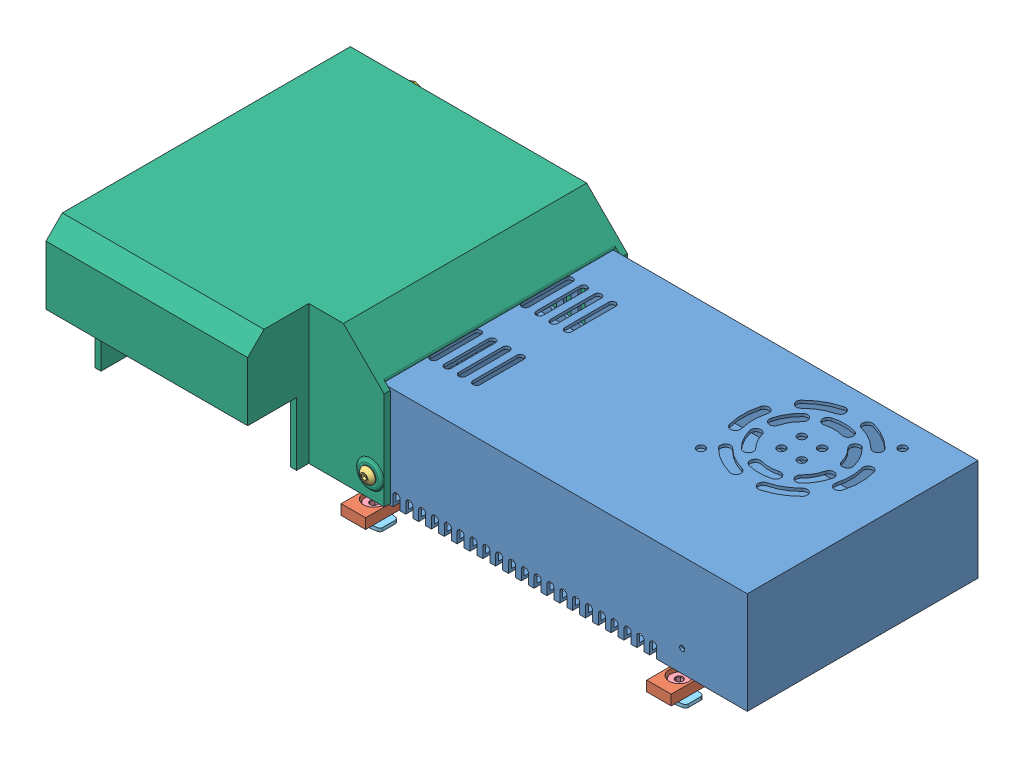
SolidWorks assembly Power_Supply ASMB, configuration Default. Lengths in mm.
21 component instances, 7 part files, 49 mates.
Components (placement in the parent):
- 360W_12V_Powersupply-1: 360W_12V_Powersupply [Default] at origin size (214 50 113.25)
- PSU Holder-1: PSU Holder [Default] at (75 0 0) x (0 0 1) z (0 -1 0) size (136 12 5)
- PSU Holder-2: PSU Holder [Default] at (-75 0 0) x (0 0 1) z (0 -1 0) size (136 12 5)
- M4 Buttonhead Bolt-1: M4 Buttonhead Bolt [M4 x 6mm] at (75 -4.2 25) x (1 0 0) z (0 -1 0) size (7.6 7.6 8.2)
- M4 Buttonhead Bolt-2: M4 Buttonhead Bolt [M4 x 6mm] at (75 -4.2 -25) x (1 0 0) z (0 -1 0) size (7.6 7.6 8.2)
- M4 Buttonhead Bolt-3: M4 Buttonhead Bolt [M4 x 6mm] at (-75 -4.2 -25) x (1 0 0) z (0 -1 0) size (7.6 7.6 8.2)
- M4 Buttonhead Bolt-4: M4 Buttonhead Bolt [M4 x 6mm] at (-75 -4.2 25) x (1 0 0) z (0 -1 0) size (7.6 7.6 8.2)
- Low Profile Screw M5-1: Low Profile Screw M5 [M5 x 8] at (75 -11 -58) x (0 -1 0) z (0 0 1) size (9.62 9 9)
- Low Profile Screw M5-2: Low Profile Screw M5 [M5 x 8] at (-75 -11 -58) x (0 -1 0) z (0 0 1) size (9.62 9 9)
- Low Profile Screw M5-3: Low Profile Screw M5 [M5 x 8] at (-75 -11 58) x (0 -1 0) z (0 0 1) size (9.62 9 9)
- Low Profile Screw M5-4: Low Profile Screw M5 [M5 x 8] at (75 -11 58) x (0 -1 0) z (0 0 1) size (9.62 9 9)
- Tee Nut-1: Tee Nut [Default] at (75 -6.8 -58) x (1 0 0) z (0 -1 0) size (15 10 3)
- Tee Nut-2: Tee Nut [Default] at (75 -6.8 58) x (1 0 0) z (0 -1 0) size (15 10 3)
- Tee Nut-3: Tee Nut [Default] at (-75 -6.8 58) x (1 0 0) z (0 -1 0) size (15 10 3)
- Tee Nut-4: Tee Nut [Default] at (-75 -6.8 -58) x (1 0 0) z (0 -1 0) size (15 10 3)
- Wiring Safety Cover-1: Wiring Safety Cover [Default] at (-144.75 65.8 -0.075) x (0 0 1) z (0 1 0) size (164.4 136 73.8)
- Amazon_Electrical_Fused_Plug-1: Amazon_Electrical_Fused_Plug [Default] at (-174.45 43.45 -59.775) x (0 1 0) z (0 0 -1) size (49 59 24.75)
- M4 Buttonhead Bolt-5: M4 Buttonhead Bolt [M4 x 8mm] at (-75 11.5 -62.975) x (-0.923728 -0.383049 0) z (0 0 -1) size (7.6 7.6 10.34)
- M4 Buttonhead Bolt-6: M4 Buttonhead Bolt [M4 x 8mm] at (-75 11.5 62.825) size (7.6 7.6 10.34)
- Low Profile Screw M5-5: Low Profile Screw M5 [M5 x 10] at (-176.25 -10 -65.775) x (0 -1 0) z (0 0 1) size (11.5 9 9)
- Tee Nut-5: Tee Nut [Default] at (-176.25 -6.8 -65.775) x (0 0 -1) z (0 -1 0) size (15 10 3)
Mates (geometry in assembly coordinates):
- Coincident1: coincident anti-aligned: plane of 360W_12V_Powersupply-1 through (0 0 0) normal (0 -1 0); plane of PSU Holder-1 through (75 0 0) normal (0 1 0)
- Coincident2: coincident anti-aligned: plane of 360W_12V_Powersupply-1 through (0 0 0) normal (0 -1 0); plane of PSU Holder-2 through (-75 0 0) normal (0 1 0)
- Concentric1: concentric anti-aligned: cylinder of 360W_12V_Powersupply-1 through (75 0 25) axis (0 -1 0) radius 1.65; cylinder of PSU Holder-1 through (75 -5 25) axis (0 1 0) radius 2.1
- Concentric2: concentric anti-aligned: cylinder of 360W_12V_Powersupply-1 through (75 0 -25) axis (0 -1 0) radius 1.65; cylinder of PSU Holder-1 through (75 -5 -25) axis (0 1 0) radius 2.1
- Concentric3: concentric anti-aligned: cylinder of 360W_12V_Powersupply-1 through (-75 0 25) axis (0 -1 0) radius 1.65; cylinder of PSU Holder-2 through (-75 -5 25) axis (0 1 0) radius 2.1
- Concentric4: concentric anti-aligned: cylinder of 360W_12V_Powersupply-1 through (-75 0 -25) axis (0 -1 0) radius 1.65; cylinder of PSU Holder-2 through (-75 -5 -25) axis (0 1 0) radius 2.1
- Concentric5: concentric anti-aligned: cylinder of 360W_12V_Powersupply-1 through (75 0 25) axis (0 -1 0) radius 1.65; cylinder of M4 Buttonhead Bolt-1 through (75 4 25) axis (0 1 0) radius 2
- Coincident3: coincident anti-aligned: plane of PSU Holder-1 through (-27.0469 -2 -48) normal (0 -1 0); plane of M4 Buttonhead Bolt-1 through (75 -2 21.2) normal (0 1 0)
- Concentric6: concentric anti-aligned: cylinder of 360W_12V_Powersupply-1 through (75 0 -25) axis (0 -1 0) radius 1.65; cylinder of M4 Buttonhead Bolt-2 through (75 4 -25) axis (0 1 0) radius 2
- Coincident4: coincident anti-aligned: plane of PSU Holder-1 through (-27.0469 -2 -48) normal (0 -1 0); plane of M4 Buttonhead Bolt-2 through (75 -2 -28.8) normal (0 1 0)
- Concentric7: concentric anti-aligned: cylinder of 360W_12V_Powersupply-1 through (-75 0 -25) axis (0 -1 0) radius 1.65; cylinder of M4 Buttonhead Bolt-3 through (-75 4 -25) axis (0 1 0) radius 2
- Coincident5: coincident anti-aligned: plane of PSU Holder-2 through (-177.0469 -2 -48) normal (0 -1 0); plane of M4 Buttonhead Bolt-3 through (-75 -2 -28.8) normal (0 1 0)
- Concentric8: concentric anti-aligned: cylinder of 360W_12V_Powersupply-1 through (-75 0 25) axis (0 -1 0) radius 1.65; cylinder of M4 Buttonhead Bolt-4 through (-75 4 25) axis (0 1 0) radius 2
- Coincident7: coincident anti-aligned: plane of PSU Holder-2 through (-177.0469 -2 -48) normal (0 -1 0); plane of M4 Buttonhead Bolt-4 through (-75 -2 21.2) normal (0 1 0)
- Concentric91: concentric anti-aligned: cylinder of PSU Holder-1 through (75 -5 -58) axis (0 1 0) radius 2.7; cylinder of Low Profile Screw M5-1 through (75 -3 -58) axis (0 -1 0) radius 2.5
- Coincident81: coincident anti-aligned: plane of PSU Holder-1 through (75 -3 -58) normal (0 1 0); plane of Low Profile Screw M5-1 through (79.1614 -3 -58) normal (0 -1 0)
- Concentric101: concentric anti-aligned: cylinder of PSU Holder-2 through (-75 -5 58) axis (0 1 0) radius 2.7; cylinder of Low Profile Screw M5-3 through (-75 -3 58) axis (0 -1 0) radius 2.5
- Coincident91: coincident anti-aligned: plane of PSU Holder-2 through (-75 -3 58) normal (0 1 0); plane of Low Profile Screw M5-3 through (-70.8386 -3 58) normal (0 -1 0)
- Concentric111: concentric anti-aligned: cylinder of PSU Holder-1 through (75 -3 58) axis (0 1 0) radius 5; cylinder of Low Profile Screw M5-4 through (75 -3 58) axis (0 -1 0) radius 2.5
- Coincident101: coincident anti-aligned: plane of PSU Holder-1 through (75 -3 58) normal (0 1 0); plane of Low Profile Screw M5-4 through (79.1614 -3 58) normal (0 -1 0)
- Concentric12: concentric anti-aligned: cylinder of PSU Holder-2 through (-75 -5 -58) axis (0 1 0) radius 2.7; cylinder of Low Profile Screw M5-2 through (-75 -3 -58) axis (0 -1 0) radius 2.5
- Coincident11: coincident anti-aligned: plane of PSU Holder-2 through (-75 -3 -58) normal (0 1 0); plane of Low Profile Screw M5-2 through (-70.8386 -3 -58) normal (0 -1 0)
- Concentric13: concentric aligned: cylinder of Low Profile Screw M5-1 through (75 -3 -58) axis (0 -1 0) radius 2.5; cylinder of Tee Nut-1 through (75 -9.8 -58) axis (0 -1 0) radius 2.1
- Concentric14: concentric aligned: cylinder of Low Profile Screw M5-4 through (75 -3 58) axis (0 -1 0) radius 2.5; cylinder of Tee Nut-2 through (75 -9.8 58) axis (0 -1 0) radius 2.1
- Concentric15: concentric aligned: cylinder of Low Profile Screw M5-3 through (-75 -3 58) axis (0 -1 0) radius 2.5; cylinder of Tee Nut-3 through (-75 -9.8 58) axis (0 -1 0) radius 2.1
- Concentric16: concentric aligned: cylinder of Low Profile Screw M5-2 through (-75 -3 -58) axis (0 -1 0) radius 2.5; cylinder of Tee Nut-4 through (-75 -9.8 -58) axis (0 -1 0) radius 2.1
- Parallel1: parallel aligned: plane of 360W_12V_Powersupply-1 through (-107 50 -56.625) normal (0 0 -1); plane of Tee Nut-1 through (72 -8.4 -63) normal (0 0 -1)
- Parallel2: parallel aligned: plane of 360W_12V_Powersupply-1 through (-107 50 -56.625) normal (0 0 -1); plane of Tee Nut-4 through (-78 -8.4 -63) normal (0 0 -1)
- Parallel3: parallel aligned: plane of 360W_12V_Powersupply-1 through (-107 50 -56.625) normal (0 0 -1); plane of Tee Nut-2 through (72 -8.4 53) normal (0 0 -1)
- Parallel4: parallel aligned: plane of 360W_12V_Powersupply-1 through (-107 50 -56.625) normal (0 0 -1); plane of Tee Nut-3 through (-78 -8.4 53) normal (0 0 -1)
- Distance1: distance = 1.8 mm anti-aligned: plane of PSU Holder-1 through (75 -5 0) normal (0 -1 0); plane of Tee Nut-1 through (81 -6.8 -55) normal (0 1 0)
- Distance2: distance = 1.8 mm anti-aligned: plane of PSU Holder-1 through (75 -5 0) normal (0 -1 0); plane of Tee Nut-2 through (81 -6.8 61) normal (0 1 0)
- Distance3: distance = 1.8 mm anti-aligned: plane of PSU Holder-1 through (75 -5 0) normal (0 -1 0); plane of Tee Nut-3 through (-69 -6.8 61) normal (0 1 0)
- Distance4: distance = 1.8 mm anti-aligned: plane of PSU Holder-1 through (75 -5 0) normal (0 -1 0); plane of Tee Nut-4 through (-69 -6.8 -55) normal (0 1 0)
- Coincident102: coincident anti-aligned: plane of 360W_12V_Powersupply-1 through (-107 50 56.625) normal (0 0 1); plane of Wiring Safety Cover-1 through (-144.75 0.8 56.625) normal (0 0 -1)
- Distance5: distance = 0 mm aligned: plane of Wiring Safety Cover-1 through (-144.75 -5 -0.075) normal (0 -1 0); plane of PSU Holder-2 through (-75 -5 0) normal (0 -1 0)
- Concentric112: concentric anti-aligned: cylinder of Wiring Safety Cover-1 through (-174.45 63.3 89.626) axis (0 0 -1) radius 1.45; cylinder of Amazon_Electrical_Fused_Plug-1 through (-174.45 63.3 -61.675) axis (0 0 1) radius 1.75
- Concentric113: concentric anti-aligned: cylinder of Wiring Safety Cover-1 through (-174.45 23.6 89.626) axis (0 0 -1) radius 1.45; cylinder of Amazon_Electrical_Fused_Plug-1 through (-174.45 23.6 -61.675) axis (0 0 1) radius 1.75
- Coincident104: coincident anti-aligned: plane of Wiring Safety Cover-1 through (-144.75 68.8 -59.775) normal (0 0 -1); plane of Amazon_Electrical_Fused_Plug-1 through (-174.45 43.45 -59.775) normal (0 0 1)
- Parallel5: parallel aligned: cylinder of 360W_12V_Powersupply-1 through (-75 11.5 -56.625) axis (0 0 -1) radius 1.25; cylinder of Wiring Safety Cover-1 through (-75 11.5 65.989) axis (0 0 -1) radius 2.25
- Concentric114: concentric aligned: cylinder of Wiring Safety Cover-1 through (-75 11.5 65.989) axis (0 0 -1) radius 2.25; cylinder of M4 Buttonhead Bolt-6 through (-75 11.5 52.625) axis (0 0 -1) radius 2
- Coincident105: coincident anti-aligned: plane of Wiring Safety Cover-1 through (-75 11.5 60.625) normal (0 0 1); plane of M4 Buttonhead Bolt-6 through (-75 7.7 60.625) normal (0 0 -1)
- Concentric115: concentric anti-aligned: cylinder of Wiring Safety Cover-1 through (-75 11.5 65.989) axis (0 0 -1) radius 2.25; cylinder of M4 Buttonhead Bolt-5 through (-75 11.5 -52.775) axis (0 0 1) radius 2
- Coincident106: coincident anti-aligned: plane of Wiring Safety Cover-1 through (-75 11.5 -60.775) normal (0 0 -1); plane of M4 Buttonhead Bolt-5 through (-73.5444 7.9898 -60.775) normal (0 0 1)
- Concentric1161: concentric aligned: cylinder of Wiring Safety Cover-1 through (-176.25 68.801 -65.775) axis (0 -1 0) radius 5; cylinder of Low Profile Screw M5-5 through (-176.25 0 -65.775) axis (0 -1 0) radius 2.5
- Coincident1071: coincident anti-aligned: plane of Wiring Safety Cover-1 through (-176.25 0 -65.775) normal (0 1 0); plane of Low Profile Screw M5-5 through (-172.0886 0 -65.775) normal (0 -1 0)
- Concentric117: concentric aligned: cylinder of Low Profile Screw M5-5 through (-176.25 0 -65.775) axis (0 -1 0) radius 2.5; cylinder of Tee Nut-5 through (-176.25 -9.8 -65.775) axis (0 -1 0) radius 2.1
- Distance6: distance = 1.8 mm anti-aligned: plane of Wiring Safety Cover-1 through (-144.75 -5 -0.075) normal (0 -1 0); plane of Tee Nut-5 through (-173.25 -6.8 -71.775) normal (0 1 0)
- Parallel6: parallel anti-aligned: plane of Wiring Safety Cover-1 through (-166.25 65.8 -0.075) normal (1 0 0); plane of Tee Nut-5 through (-181.25 -8.4 -62.775) normal (-1 0 0)
